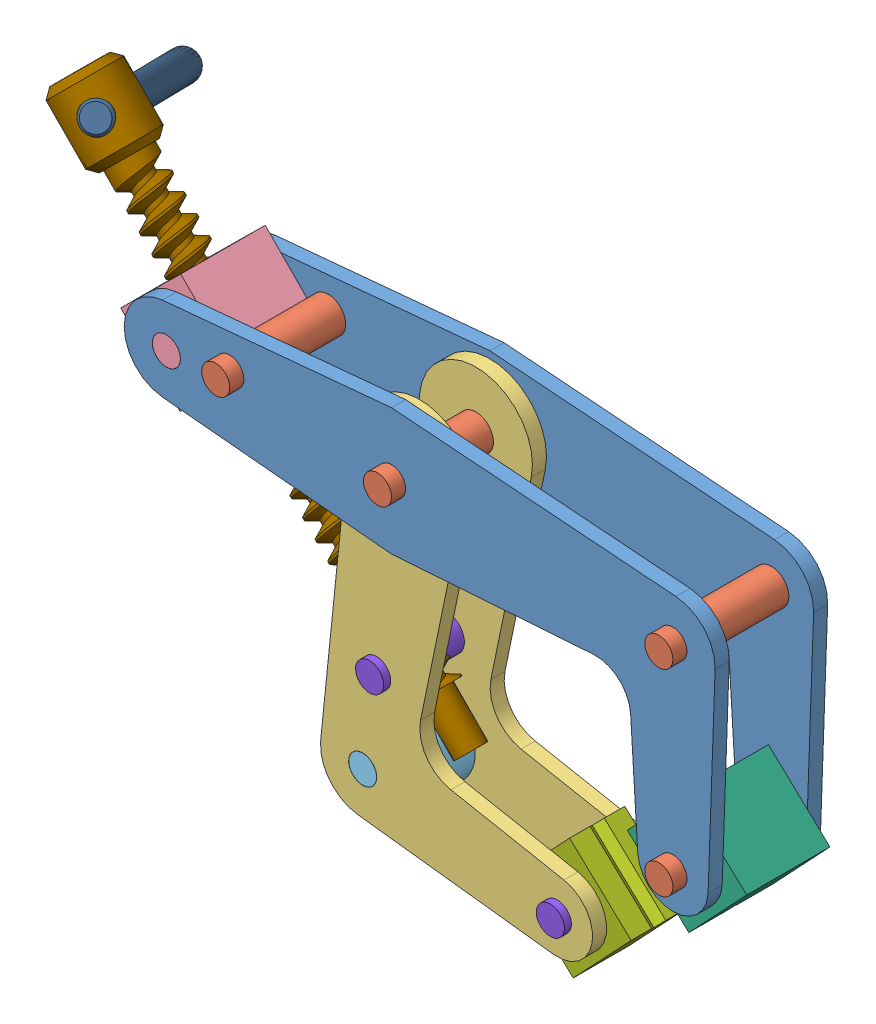
SolidWorks assembly Assem(not functional), configuration Default. Lengths in mm.
Overall size (73.62 48.29 25.98).
16 component instances, 10 part files, 32 mates.
Components (placement in the parent):
- LONG_ARM-1: LONG_ARM [Default] at origin size (52.5 26.26 1.25)
- EYE_PIN-1: EYE_PIN [Default] at (0 -17.5 -3.75) x (0.843941 0.536436 0) z (0 0 1) size (3.1 3.1 12.5)
- EYE_PIN-2: EYE_PIN [Default] at (0 0 -3.75) size (3.1 3.1 12.5)
- EYE_PIN-3: EYE_PIN [Default] at (-39.37 1.25 -3.75) x (-0.039048 -0.999237 0) z (0 0 1) size (3.1 3.1 12.5)
- EYE_PIN-4: EYE_PIN [Default] at (-25 0 -3.75) x (0.948314 -0.317334 0) z (0 0 1) size (3.1 3.1 12.5)
- SHORT_ARM-1: SHORT_ARM [Default] at (-28.8105 -24.7079 0) x (0.152422 0.988316 0) z (0 0 -1) size (33.77 25.65 1.25)
- THREAD_PIN-1: THREAD_PIN [Default] at (-45 0 -3.75) x (0.710902 0.703292 0) z (0 0 1) size (7.5 8.59 10)
- HINGE_BOLT-1: HINGE_BOLT [Default] at (-28.8105 -24.7079 -3.75) x (-0.548063 0.836437 0) z (0 0 1) size (6.88 7.5 7.5)
- WIDE_PAD-1: WIDE_PAD [Default] at (0 -17.5 -7.4) x (-0.728153 0.685414 0) z (0 0 1) size (7.5 7.5 7.4)
- NARROW_PAD-1: NARROW_PAD [Default] at (-11.515 -27.3753 -6.15) x (0.728153 -0.685414 0) z (0 0 1) size (7.5 7.5 4.9)
- RIB_PIN-1: RIB_PIN [Default] at (-27.5714 -16.6729 -3.75) x (0.983876 -0.178854 0) z (0 0 1) size (3.1 3.1 8.75)
- RIB_PIN-2: RIB_PIN [Default] at (-11.515 -27.3753 -3.75) size (3.1 3.1 8.75)
- SHORT_ARM-2: SHORT_ARM [Default] at (-28.8105 -24.7079 -6.25) x (0.152422 0.988316 0) z (0 0 -1) size (33.77 25.65 1.25)
- LONG_ARM-2: LONG_ARM [Default] at (0 0 -8.75) size (52.5 26.26 1.25)
- THREADED_SHAFT-1: THREADED_SHAFT [Default] at (-57.6818 12.819 -3.75) x (-0.534819 -0.529094 0.658808) z (0.703292 -0.710902 0) size (5.63 5.63 49.38)
- PF_SHAFT-1: PF_SHAFT [Default] at (-60.6054 5.5309 -11.9765) x (0.871726 -0.103519 -0.478934) z (-0.468348 -0.463334 -0.752311) size (2.5 2.5 27.5)
Mates (geometry in assembly coordinates):
- Parallel1: parallel anti-aligned: plane of LONG_ARM-1 through (-45 0 1.25) normal (0 0 1); plane of SHORT_ARM-1 through (-11.515 -27.3753 -1.25) normal (0 0 -1)
- Coincident3: coincident anti-aligned: plane of LONG_ARM-1 through (-45 0 0) normal (0 0 -1); plane of SHORT_ARM-1 through (-11.515 -27.3753 0) normal (0 0 1)
- Concentric2: concentric anti-aligned: cylinder of LONG_ARM-1 through (-25 0 1.25) axis (0 0 -1) radius 1.25; cylinder of SHORT_ARM-1 through (-25 0 -1.25) axis (0 0 1) radius 1.56
- Concentric3: concentric aligned: cylinder of LONG_ARM-1 through (-25 0 1.25) axis (0 0 -1) radius 1.25; cylinder of EYE_PIN-4 through (-25 0 2.5) axis (0 0 -1) radius 1.25
- Concentric4: concentric aligned: cylinder of LONG_ARM-1 through (-39.37 1.25 1.25) axis (0 0 -1) radius 1.25; cylinder of EYE_PIN-3 through (-39.37 1.25 2.5) axis (0 0 -1) radius 1.25
- Coincident6: coincident anti-aligned: plane of LONG_ARM-1 through (-45 0 0) normal (0 0 -1); plane of EYE_PIN-3 through (-39.37 1.25 0) normal (0 0 1)
- Coincident7: coincident anti-aligned: plane of LONG_ARM-1 through (-45 0 0) normal (0 0 -1); plane of EYE_PIN-4 through (-25 0 0) normal (0 0 1)
- Coincident8: coincident anti-aligned: plane of LONG_ARM-1 through (-45 0 0) normal (0 0 -1); plane of THREAD_PIN-1 through (-45 0 0) normal (0 0 1)
- Concentric5: concentric aligned: cylinder of LONG_ARM-1 through (-45 0 1.25) axis (0 0 -1) radius 1.25; cylinder of THREAD_PIN-1 through (-45 0 1.25) axis (0 0 -1) radius 1.245
- Coincident10: coincident anti-aligned: plane of SHORT_ARM-1 through (-11.515 -27.3753 -1.25) normal (0 0 -1); plane of HINGE_BOLT-1 through (-28.8105 -24.7079 -1.25) normal (0 0 1)
- Concentric8: concentric anti-aligned: cylinder of SHORT_ARM-1 through (-28.8105 -24.7079 -1.25) axis (0 0 1) radius 1.25; cylinder of HINGE_BOLT-1 through (-28.8105 -24.7079 0) axis (0 0 -1) radius 1.24
- Concentric11: concentric aligned: cylinder of LONG_ARM-1 through (0 0 1.25) axis (0 0 -1) radius 1.25; cylinder of EYE_PIN-2 through (0 0 2.5) axis (0 0 -1) radius 1.25
- Coincident13: coincident anti-aligned: plane of LONG_ARM-1 through (-45 0 0) normal (0 0 -1); plane of EYE_PIN-2 through (0 0 0) normal (0 0 1)
- Concentric12: concentric anti-aligned: cylinder of SHORT_ARM-1 through (-27.5714 -16.6729 -1.25) axis (0 0 1) radius 1.25; cylinder of RIB_PIN-1 through (-27.5714 -16.6729 0.625) axis (0 0 -1) radius 1.25
- Coincident14: coincident anti-aligned: plane of SHORT_ARM-1 through (-11.515 -27.3753 -1.25) normal (0 0 -1); plane of RIB_PIN-1 through (-27.5714 -16.6729 -1.25) normal (0 0 1)
- Concentric13: concentric anti-aligned: cylinder of SHORT_ARM-1 through (-11.515 -27.3753 -1.25) axis (0 0 1) radius 1.25; cylinder of RIB_PIN-2 through (-11.515 -27.3753 0.625) axis (0 0 -1) radius 1.25
- Coincident15: coincident anti-aligned: plane of SHORT_ARM-1 through (-11.515 -27.3753 -1.25) normal (0 0 -1); plane of RIB_PIN-2 through (-11.515 -27.3753 -1.25) normal (0 0 1)
- Coincident16: coincident anti-aligned: plane of SHORT_ARM-1 through (-11.515 -27.3753 -1.25) normal (0 0 -1); plane of NARROW_PAD-1 through (-11.515 -27.3753 -1.25) normal (0 0 1)
- Concentric14: concentric aligned: cylinder of NARROW_PAD-1 through (-11.515 -27.3753 -1.25) axis (0 0 -1) radius 1.56; cylinder of RIB_PIN-2 through (-11.515 -27.3753 -1.25) axis (0 0 -1) radius 1.55
- Concentric15: concentric aligned: cylinder of LONG_ARM-1 through (0 -17.5 1.25) axis (0 0 -1) radius 1.25; cylinder of EYE_PIN-1 through (0 -17.5 2.5) axis (0 0 -1) radius 1.25
- Coincident17: coincident anti-aligned: plane of LONG_ARM-1 through (-45 0 0) normal (0 0 -1); plane of EYE_PIN-1 through (0 -17.5 0) normal (0 0 1)
- Concentric16: concentric aligned: cylinder of EYE_PIN-1 through (0 -17.5 0) axis (0 0 -1) radius 1.55; cylinder of WIDE_PAD-1 through (0 -17.5 0) axis (0 0 -1) radius 1.56
- Coincident18: coincident anti-aligned: plane of LONG_ARM-1 through (-45 0 0) normal (0 0 -1); plane of WIDE_PAD-1 through (0 -17.5 0) normal (0 0 1)
- Coincident19: coincident anti-aligned: plane of HINGE_BOLT-1 through (-28.8105 -24.7079 -6.25) normal (0 0 -1); plane of SHORT_ARM-2 through (-11.515 -27.3753 -6.25) normal (0 0 1)
- Concentric17: concentric aligned: cylinder of RIB_PIN-2 through (-11.515 -27.3753 -8.125) axis (0 0 1) radius 1.25; cylinder of SHORT_ARM-2 through (-11.515 -27.3753 -7.5) axis (0 0 1) radius 1.25
- Concentric18: concentric aligned: cylinder of HINGE_BOLT-1 through (-28.8105 -24.7079 -7.5) axis (0 0 1) radius 1.24; cylinder of SHORT_ARM-2 through (-28.8105 -24.7079 -7.5) axis (0 0 1) radius 1.25
- Concentric19: concentric aligned: cylinder of RIB_PIN-1 through (-27.5714 -16.6729 -8.125) axis (0 0 1) radius 1.25; cylinder of SHORT_ARM-2 through (-27.5714 -16.6729 -7.5) axis (0 0 1) radius 1.25
- Coincident28: coincident anti-aligned: plane of THREAD_PIN-1 through (-45 0 -7.5) normal (0 0 -1); plane of LONG_ARM-2 through (-45 0 -7.5) normal (0 0 1)
- Concentric20: concentric anti-aligned: cylinder of THREAD_PIN-1 through (-45 0 -8.75) axis (0 0 1) radius 1.245; cylinder of LONG_ARM-2 through (-45 0 -7.5) axis (0 0 -1) radius 1.25
- Concentric24: concentric anti-aligned: cylinder of THREADED_SHAFT-1 through (-54.1656 11.9017 -1.6322) axis (-0.468348 -0.463334 -0.752311) radius 1.245; cylinder of PF_SHAFT-1 through (-67.0452 -0.8399 -22.3208) axis (0.468348 0.463334 0.752311) radius 1.25
- Tangent3: tangent aligned: cylinder of THREADED_SHAFT-1 through (-53.2862 8.3759 -3.75) axis (-0.703292 0.710902 0) radius 2.815; plane of PF_SHAFT-1 through (-54.1656 11.9017 -1.6322) normal (0.468348 0.463334 0.752311)
- Screw1: screw = 1 aligned: cylinder of THREAD_PIN-1 through (-42.3627 -2.6659 -3.75) axis (-0.703292 0.710902 0) radius 1.565; cylinder of THREADED_SHAFT-1 through (-26.0337 -19.1715 -3.75) axis (-0.703292 0.710902 0) radius 1.875
